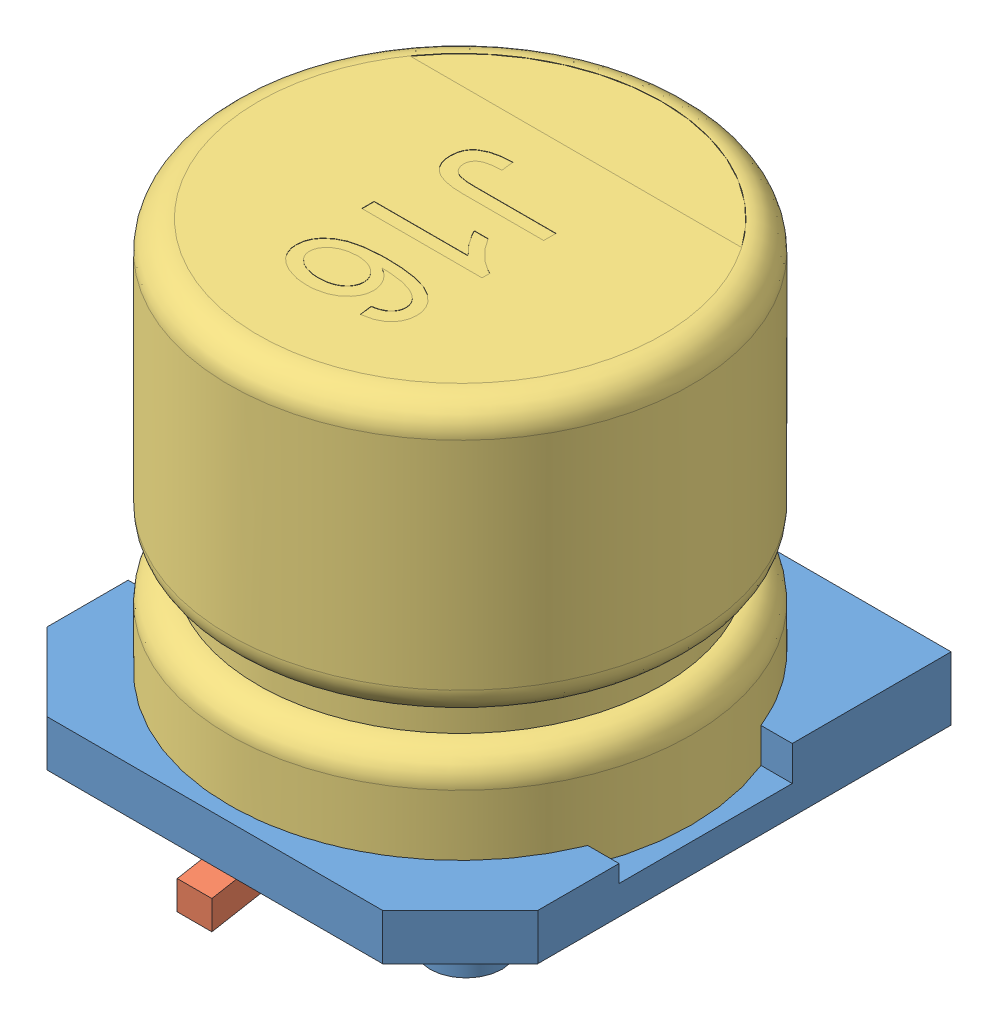
SolidWorks assembly SMD-CAP-ALU-J16, configuration Default. Lengths in mm.
Overall size (17 16.5 18.4).
4 component instances, 3 part files, 9 mates.
Components (placement in the parent):
- Foot-1: Foot [Default] at origin size (17 3.5 17)
- P-1: P [Default] at (0 1 9.2) x (0 -1 0) z (0 0 1) size (2 1.2 5.5)
- P-2: P [Default] at (0 1 -9.2) x (0 -1 0) z (0 0 -1) size (2 1.2 5.5)
- CAN-1: CAN [Default] at (0 2.3 0) x (0 0 1) z (-1 0 0) size (16 14.2 16)
Mates (geometry in assembly coordinates):
- Distance1: distance = 0 mm: plane of assembly through (0 0 0) normal (0 1 0); plane of Foot-1 through (0 0 0) normal (0 -1 0)
- Coincident2: coincident: plane of Foot-1 through (0 0 0) normal (0 0 1); plane of assembly through (0 0 0) normal (0 0 1)
- Coincident3: coincident: plane of Foot-1 through (0 0 0) normal (1 0 0); plane of assembly through (0 0 0) normal (1 0 0)
- Coincident5: coincident: plane of P-1 through (0 1 9.2) normal (1 0 0); plane of assembly through (0 0 0) normal (1 0 0)
- Distance3: distance = 0.7 mm: plane of P-1 through (0.6 1 9.2) normal (0 0 1); plane of Foot-1 through (-8.5 3.5 8.5) normal (0 0 1)
- Coincident8: coincident: line of P-1 through (0.6 0 9.2) axis (-1 0 0); plane of assembly
- Coincident12: coincident: plane of CAN-1 through (0 2.3 0) normal (-1 0 0); plane of assembly through (0 0 0) normal (1 0 0)
- Coincident13: coincident: plane of CAN-1 through (0 2.3 0) normal (0 0 1); plane of assembly through (0 0 0) normal (0 0 1)
- Coincident14: coincident: plane of Foot-1 through (0 2.3 0) normal (0 1 0); plane of CAN-1 through (0 2.3 0) normal (0 -1 0)
